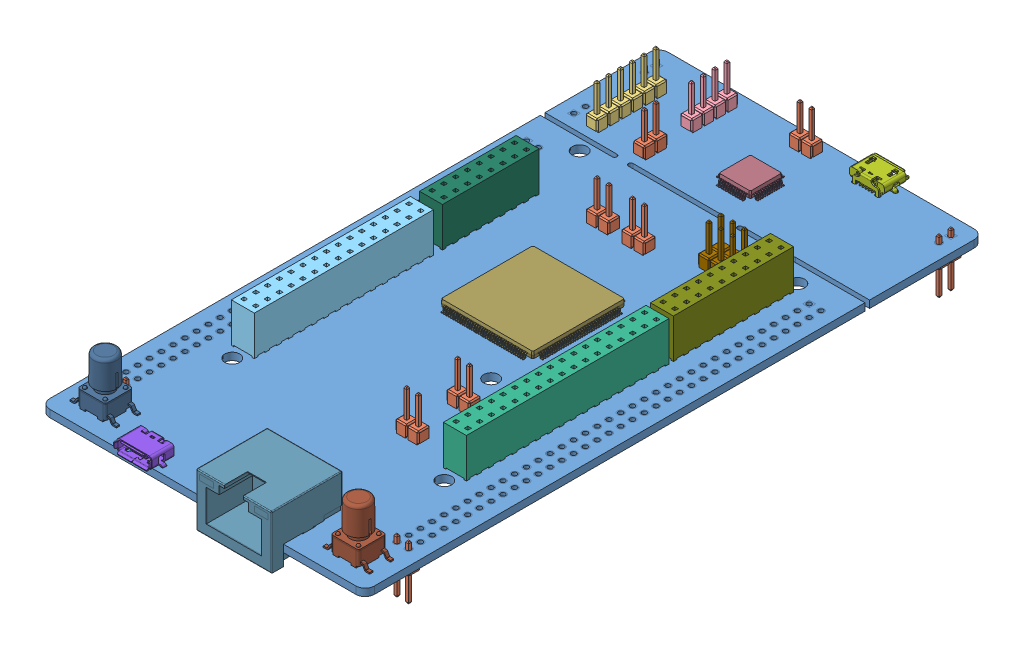
SolidWorks assembly NUCLEO-F429ZI--3DModel-STEP-56544, configuration Default. Lengths in mm.
Overall size (70 20.82 136.99).
25 component instances, 16 part files, 0 mates.
Components (placement in the parent):
- NUCLEO-F429ZI board-1: NUCLEO-F429ZI board [Default] at origin size (70 1.58 133.34)
- jp1-1: jp1 [Default] at (-1.27 1.58 -63.37) size (5.08 11.6 2.54)
- jp1-2: jp1 [Default] at (-16.55 1.58 -45.09) x (0 0 -1) z (1 0 0) size (5.08 11.6 2.54)
- cn6-1: cn6 [Default] at (-26.75 1.58 -45.07) x (0 0 -1) z (1 0 0) size (15.24 11.6 2.54)
- cn4-1: cn4 [Default] at (-16.55 1.58 -55.25) x (0 0 -1) z (1 0 0) size (10.16 11.6 2.54)
- cn9-1: cn9 [Default] at (-22.86 1.58 15.87) x (0 0 -1) z (1 0 0) size (38.61 13.34 4.95)
- cn10-1: cn10 [Default] at (22.86 1.58 13.33) x (0 0 -1) z (1 0 0) size (43.69 13.34 4.95)
- jp1-3: jp1 [Default] at (-31.75 0 -62.87) x (0 0 1) z (1 0 0) size (5.08 11.6 2.54)
- jp1-4: jp1 [Default] at (31.75 0 -60.33) x (0 0 -1) z (-1 0 0) size (5.08 11.6 2.54)
- cn1-1: cn1 [Default] at (13.9 2.805 -64.97) x (-1 0 0) z (0 0 -1) size (8.2 3.3 5.4)
- cn13-1: cn13 [Default] at (-15.6 1.88 63.62) x (-1 0 0) z (0 0 -1) size (8.66 3.36 5.9)
- jp3-1: jp3 [Default] at (11.45 1.58 -33.61) size (7.62 11.6 5.08)
- jp1-5: jp1 [Default] at (-8.91 1.58 -27.27) size (5.08 11.6 2.54)
- jp1-6: jp1 [Default] at (-1.27 1.58 -27.27) size (5.08 11.6 2.54)
- jp1-7: jp1 [Default] at (-29.21 0 54.03) x (-1 0 0) z (0 0 1) size (5.08 11.6 2.54)
- jp1-8: jp1 [Default] at (31.75 0 54.03) x (-1 0 0) z (0 0 1) size (5.08 11.6 2.54)
- b1-1: b1 [Default] at (-27.3 1.58 60.4) x (0 0 -1) z (1 0 0) size (6 10.7 10)
- b2-1: b2 [Default] at (27.3 1.58 60.4) x (0 0 -1) z (1 0 0) size (6 10.7 10)
- jp1-9: jp1 [Default] at (9.79 1.58 21.49) size (5.08 11.6 2.54)
- jp1-10: jp1 [Default] at (9.79 1.58 32.49) size (5.08 11.6 2.54)
- STM32lqfp144-1: STM32lqfp144 [Default] at (0 2.4349 -4.5) size (21.95 1.58 21.95)
- STM32F103CBT6-1: STM32F103CBT6 [Default] at (0 2.4349 -51.4) size (9 1.6 9)
- lan-1: lan [Default] at (9.3 3.13 69.27) size (16.2 11.5 15.3)
- cn8-1: cn8 [Default] at (-22.86 1.58 -15.8) x (0 0 -1) z (1 0 0) size (20.83 13.33 4.95)
- cn7-1: cn7 [Default] at (22.86 1.58 -22.42) x (0 0 -1) z (1 0 0) size (25.91 13.33 4.95)
